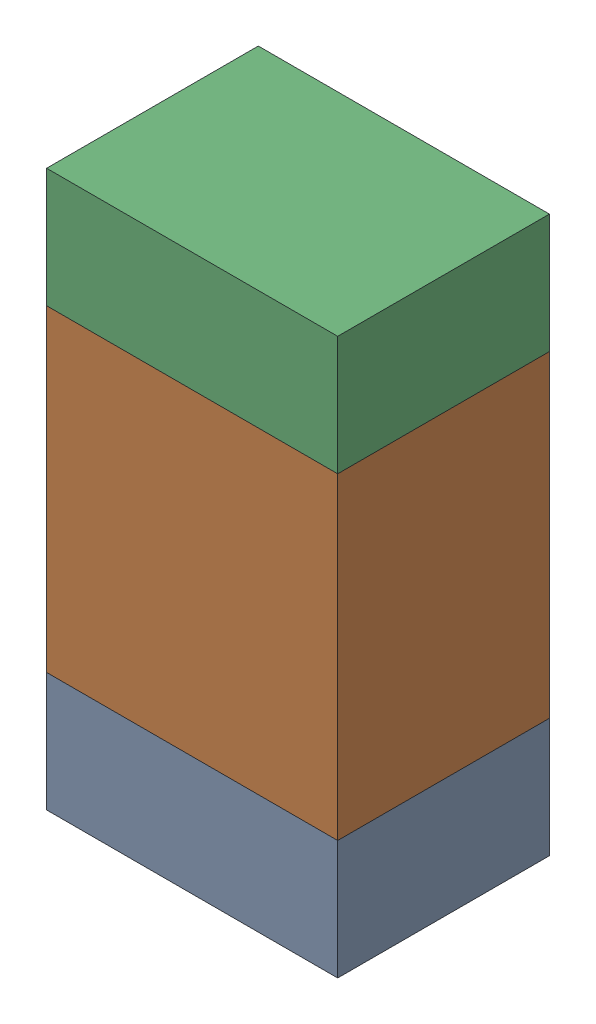
SolidWorks assembly R308_1PCB, configuration Default. Lengths in mm.
Overall size (0.55 1.05 0.4).
6 component instances, 2 part files, 0 mates.
Components (placement in the parent):
- 846483288-1: 846483288 [Default] at (128.4001 110.1876 0) size (0.55 0.22 0.4)
  - Extruded_12-1: Extruded_12 [Default] at origin size (0.55 0.22 0.4)
- 846483424-1: 846483424 [Default] at (128.4001 110.6001 0) size (0.55 0.6 0.4)
  - Extruded_13-1: Extruded_13 [Default] at origin size (0.55 0.6 0.4)
- 846483288-2: 846483288 [Default] at (128.4001 111.0126 0) size (0.55 0.22 0.4)
  - Extruded_12-1: Extruded_12 [Default] at origin size (0.55 0.22 0.4)
